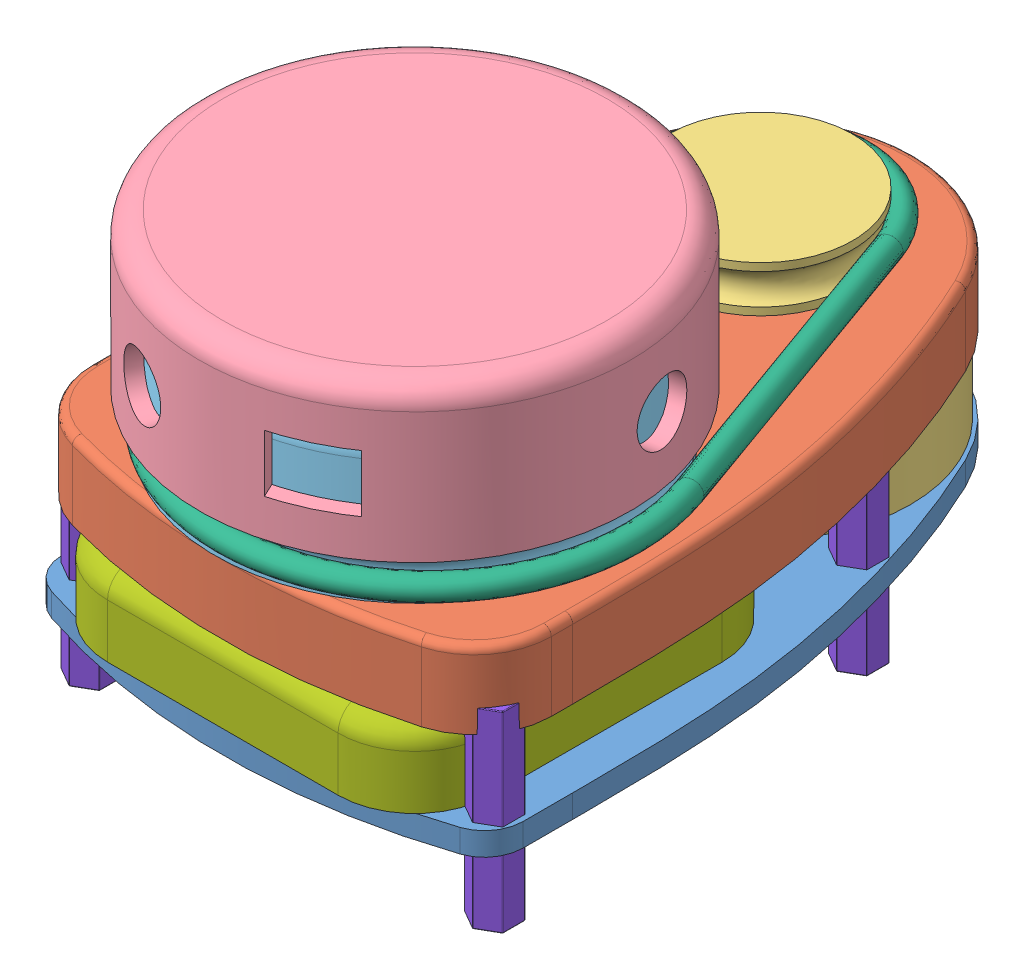
SolidWorks assembly 思岚激光雷达a1装配体, configuration 默认. Lengths in mm.
Overall size (65.95 58.1 98.76).
11 component instances, 8 part files, 17 mates.
Components (placement in the parent):
- 思岚激光雷达a1底-1: 思岚激光雷达a1底 [默认] at origin size (60 3 90)
- 思岚激光雷达a1壳-1: 思岚激光雷达a1壳 [默认] at (0 13 0) x (1 0 0) z (0 1 0) size (65.95 90 12.92)
- 思岚激光雷达a1电机-1: 思岚激光雷达a1电机 [默认] at (0 3 0) x (0.986803 0 -0.161926) z (0.161926 0 0.986803) size (39 26 39)
- 激光雷达-1: 激光雷达 [默认] at (0 29 45) x (0.08485 0 -0.996394) z (0.996394 0 0.08485) size (56 20 56)
- 激光雷达转子-1: 激光雷达转子 [默认] at (0 23 45) x (0.972302 0 0.233728) z (-0.233728 0 0.972302) size (52 21 52)
- 激光雷达转子带-1: 激光雷达转子带 [默认] at (1.7749 26.1024 44.965) x (-0.039442 0 -0.999222) z (0.999222 0 -0.039442) size (87.5 3 56)
- 思岚激光雷达a1内部-1: 思岚激光雷达a1内部 [默认] at (0 3 45) size (50 10 50)
- 铜柱-1: 铜柱 [默认] at (26.8208 -9 61.4324) size (5 30.2 5.74)
- 铜柱-2: 铜柱 [默认] at (-22.4663 -9 8.7845) size (5 30.2 5.74)
- 铜柱-3: 铜柱 [默认] at (21.5205 -9 8.746) size (5 30.2 5.74)
- 铜柱-4: 铜柱 [默认] at (-26.7706 -9 60.3423) size (5 30.2 5.74)
Mates (geometry in assembly coordinates):
- 同心1: concentric: cylinder of assembly; cylinder of assembly; cylinder of 思岚激光雷达a1底-1 through (0 3 0) axis (0 -1 0) radius 20; cylinder of 思岚激光雷达a1壳-1 through (0 23 0) axis (0 -1 0) radius 20
- 同心2: concentric: cylinder of assembly; cylinder of assembly; cylinder of 思岚激光雷达a1底-1 through (0 3 -14) axis (0 -1 0) radius 84; cylinder of 思岚激光雷达a1壳-1 through (0 23 -14) axis (0 -1 0) radius 84
- 距离1: distance = 10 mm: plane of assembly; plane of assembly; plane of 思岚激光雷达a1壳-1 through (0 13 0) normal (0 -1 0); plane of 思岚激光雷达a1底-1 through (0 3 0) normal (0 1 0)
- 同心3: concentric: cylinder of assembly; cylinder of assembly; cylinder of 思岚激光雷达a1壳-1 through (0 13 0) axis (0 1 0) radius 7.5; cylinder of 思岚激光雷达a1电机-1 through (0 23 0) axis (0 -1 0) radius 5
- 重合2: coincident: plane of assembly; plane of assembly; plane of 思岚激光雷达a1底-1 through (0 3 0) normal (0 1 0); plane of 思岚激光雷达a1电机-1 through (0 3 0) normal (0 -1 0)
- 同心4: concentric: cylinder of assembly; cylinder of assembly; cylinder of 思岚激光雷达a1壳-1 through (0 13 45) axis (0 1 0) radius 7.5; cylinder of 激光雷达-1 through (0 29 45) axis (0 -1 0) radius 25
- 重合3: coincident: plane of assembly; plane of assembly; plane of 思岚激光雷达a1电机-1 through (0 29 0) normal (0 1 0); plane of 激光雷达-1 through (0 29 45) normal (0 -1 0)
- 同心5: concentric: cylinder of assembly; cylinder of assembly; cylinder of 激光雷达-1 through (0 29 45) axis (0 -1 0) radius 25; cylinder of 激光雷达转子-1 through (0 23 45) axis (0 -1 0) radius 26
- 重合4: coincident: plane of assembly; plane of assembly; plane of 思岚激光雷达a1壳-1 through (0 23 0) normal (0 1 0); plane of 激光雷达转子-1 through (0 23 45) normal (0 -1 0)
- 同心6: concentric: circle of assembly; circle of assembly; circle of 思岚激光雷达a1电机-1; circle of 激光雷达转子带-1
- 同心7: concentric: cylinder of assembly; cylinder of assembly; cylinder of 思岚激光雷达a1壳-1 through (0 13 45) axis (0 1 0) radius 7.5; cylinder of 思岚激光雷达a1内部-1 through (0 3 45) axis (0 1 0) radius 5
- 重合5: coincident: plane of assembly; plane of assembly; plane of 思岚激光雷达a1底-1 through (0 3 0) normal (0 1 0); plane of 思岚激光雷达a1内部-1 through (0 3 45) normal (0 -1 0)
- 平行1: parallel: plane of assembly through (0 0 0) normal (0 0 1); plane of 思岚激光雷达a1内部-1 through (-25 13 70) normal (0 0 1); plane of assembly
- 重合7: coincident: plane of assembly; plane of assembly; plane of 铜柱-1 through (26.8208 21 61.4324) normal (0 1 0); plane of 铜柱-4 through (-26.7706 21 60.3423) normal (0 1 0)
- 重合8: coincident: plane of assembly; plane of assembly; plane of 铜柱-2 through (-22.4663 21 8.7845) normal (0 1 0); plane of 铜柱-3 through (21.5205 21 8.746) normal (0 1 0)
- 重合9: coincident: plane of assembly; plane of assembly; plane of 铜柱-1 through (26.8208 21 61.4324) normal (0 1 0); plane of 铜柱-2 through (-22.4663 21 8.7845) normal (0 1 0)
- 重合10: coincident: plane of assembly; plane of assembly; plane of 思岚激光雷达a1壳-1 through (0 21 0) normal (0 -1 0); plane of 铜柱-1 through (26.8208 21 61.4324) normal (0 1 0)
